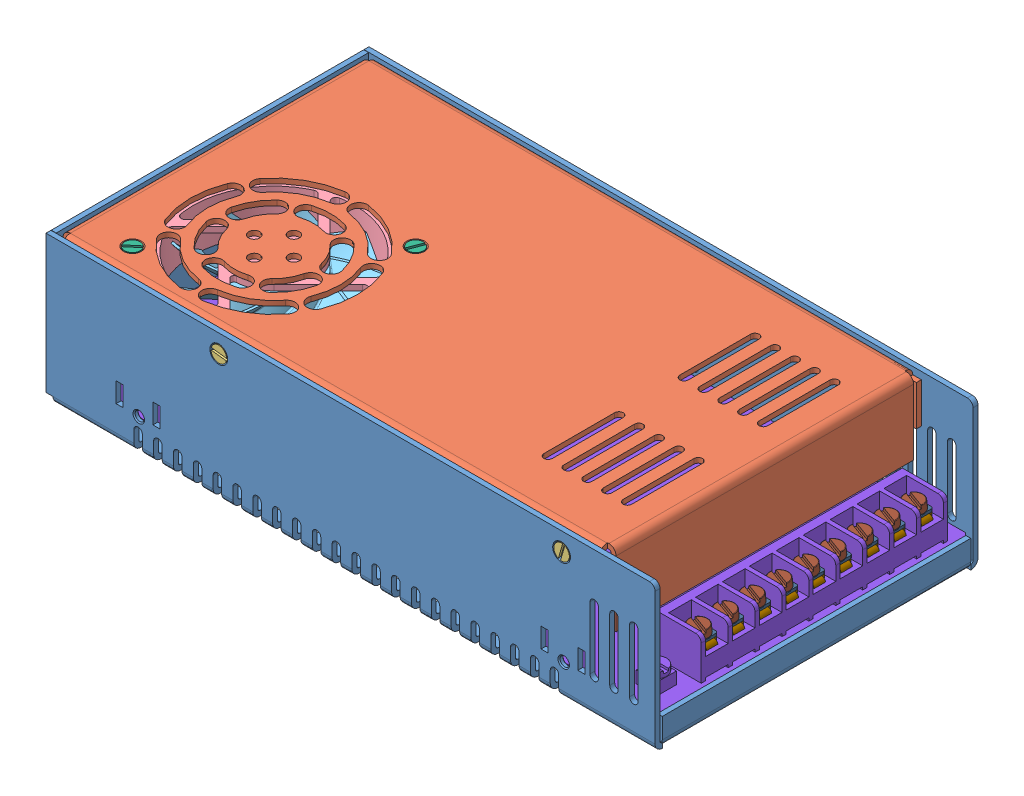
SolidWorks assembly PSU, configuration Default. Lengths in mm.
Overall size (215 51.25 117.38).
46 component instances, 12 part files, 0 mates.
Components (placement in the parent):
- SWP (Basis)-1: SWP (Basis) [Default] at (0 1.75 57) x (1 0 0) z (0 1 0) size (215 114 51.25)
- SWP (Deksel)-1: SWP (Deksel) [Default] at (-18.25 51.25 57) x (1 0 0) z (0 1 0) size (195 110.5 25.75)
- Slotted Countersunk Flat Head Screw_DIN_ISO 2009 - M3 x 5 --- 5N-1: Slotted Countersunk Flat Head Screw_DIN_ISO 2009 - M3 x 5 --- 5N [Default] at (-154 44.75 114) x (0 0 -1) z (-0.992092 0.125515 0) size (5 5.5 5.44)
- Slotted Countersunk Flat Head Screw_DIN_ISO 2009 - M3 x 5 --- 5N-2: Slotted Countersunk Flat Head Screw_DIN_ISO 2009 - M3 x 5 --- 5N [Default] at (-33 44.75 114) x (0 0 -1) z (0.278156 0.960536 0) size (5 5.5 5.44)
- Slotted Countersunk Flat Head Screw_DIN_ISO 2009 - M3 x 5 --- 5N-3: Slotted Countersunk Flat Head Screw_DIN_ISO 2009 - M3 x 5 --- 5N [Default] at (-154 44.75 0) x (0 0 1) z (0 1 0) size (5 5.5 5.44)
- Slotted Countersunk Flat Head Screw_DIN_ISO 2009 - M3 x 5 --- 5N-4: Slotted Countersunk Flat Head Screw_DIN_ISO 2009 - M3 x 5 --- 5N [Default] at (-33 44.75 0) x (0 0 1) z (-0.877705 -0.479201 0) size (5 5.5 5.44)
- Slotted Countersunk Flat Head Screw_DIN_ISO 2009 - M3 x 5 --- 5N-5: Slotted Countersunk Flat Head Screw_DIN_ISO 2009 - M3 x 5 --- 5N [Default] at (-215 44.75 102) x (1 0 0) z (0 0.869235 -0.494399) size (5 5.5 5.44)
- Slotted Countersunk Flat Head Screw_DIN_ISO 2009 - M3 x 5 --- 5N-6: Slotted Countersunk Flat Head Screw_DIN_ISO 2009 - M3 x 5 --- 5N [Default] at (-215 44.75 12) x (1 0 0) z (0 0.76206 0.647506) size (5 5.5 5.44)
- Body 60mm fan-1: Body 60mm fan [Default] at (-170.75 34.3 77.75) x (1 0 0) z (0 1 0) size (59.5 59.5 15.2)
- Propellor 60mm fan-1: Propellor 60mm fan [Default] at (-170.75 44.3 77.75) x (0.544808 0 -0.838561) z (0 1 0) size (57.61 57.23 10.49)
- Slotted Countersunk Flat Head Screw_DIN_ISO 2009 - M3 x 20 --- 20N-1: Slotted Countersunk Flat Head Screw_DIN_ISO 2009 - M3 x 20 --- 20N [Default] at (-145.75 51.25 52.75) x (0 -1 0) z (0.364765 0 -0.9311) size (20 5.5 5.44)
- Slotted Countersunk Flat Head Screw_DIN_ISO 2009 - M3 x 20 --- 20N-2: Slotted Countersunk Flat Head Screw_DIN_ISO 2009 - M3 x 20 --- 20N [Default] at (-195.75 51.25 102.75) x (0 -1 0) z (0.762204 0 -0.647337) size (20 5.5 5.44)
- SWP (M3 moer)-1: SWP (M3 moer) [Default] at (-205 0 104.5) x (1 0 0) z (0 1 0) size (8.08 7 3.75)
- SWP (M3 moer)-2: SWP (M3 moer) [Default] at (-205 0 9.5) x (1 0 0) z (0 1 0) size (8.08 7 3.75)
- SWP (M3 moer)-3: SWP (M3 moer) [Default] at (-117.5 0 50.05) x (1 0 0) z (0 1 0) size (8.08 7 3.75)
- SWP (M3 moer)-4: SWP (M3 moer) [Default] at (-27.5 0 104.5) x (1 0 0) z (0 1 0) size (8.08 7 3.75)
- SWP (M3 moer)-5: SWP (M3 moer) [Default] at (-27.5 0 9.5) x (1 0 0) z (0 1 0) size (8.08 7 3.75)
- SWP (PCB)-1: SWP (PCB) [Default] at (-1.75 9.75 57) x (1 0 0) z (0 1 0) size (211.5 110.5 15.9)
- SWP (Montage draad)_1-1: SWP (Montage draad)_1 [Default] at (-9.8 18.4 88.95) x (0 0 1) z (0 1 0) size (7 9.9 4.25)
- SWP (Montage draad 2)_1-1: SWP (Montage draad 2)_1 [Default] at (-9.8 18.4 88.95) x (1 0 0) z (0 1 0) size (7 7 1)
- Slotted Cheese Head Screw_DIN_ISO 1207 - M4 x 5 --- 5N-1: Slotted Cheese Head Screw_DIN_ISO 1207 - M4 x 5 --- 5N [Default] at (-9.8 22 88.95) x (0 -1 0) z (0.939291 0 0.343123) size (7.61 7 7)
- SWP (Montage draad)_1-2: SWP (Montage draad)_1 [Default] at (-9.8 18.4 79.45) x (0 0 1) z (0 1 0) size (7 9.9 4.25)
- SWP (Montage draad)_1-3: SWP (Montage draad)_1 [Default] at (-9.8 18.4 69.95) x (0 0 1) z (0 1 0) size (7 9.9 4.25)
- SWP (Montage draad)_1-4: SWP (Montage draad)_1 [Default] at (-9.8 18.4 60.45) x (0 0 1) z (0 1 0) size (7 9.9 4.25)
- SWP (Montage draad)_1-5: SWP (Montage draad)_1 [Default] at (-9.8 18.4 50.95) x (0 0 1) z (0 1 0) size (7 9.9 4.25)
- SWP (Montage draad)_1-6: SWP (Montage draad)_1 [Default] at (-9.8 18.4 41.45) x (0 0 1) z (0 1 0) size (7 9.9 4.25)
- SWP (Montage draad)_1-7: SWP (Montage draad)_1 [Default] at (-9.8 18.4 31.95) x (0 0 1) z (0 1 0) size (7 9.9 4.25)
- SWP (Montage draad)_1-8: SWP (Montage draad)_1 [Default] at (-9.8 18.4 22.45) x (0 0 1) z (0 1 0) size (7 9.9 4.25)
- SWP (Montage draad)_1-9: SWP (Montage draad)_1 [Default] at (-9.8 18.4 12.95) x (0 0 1) z (0 1 0) size (7 9.9 4.25)
- SWP (Montage draad 2)_1-2: SWP (Montage draad 2)_1 [Default] at (-9.8 18.4 79.45) x (1 0 0) z (0 1 0) size (7 7 1)
- SWP (Montage draad 2)_1-3: SWP (Montage draad 2)_1 [Default] at (-9.8 18.4 69.95) x (1 0 0) z (0 1 0) size (7 7 1)
- SWP (Montage draad 2)_1-4: SWP (Montage draad 2)_1 [Default] at (-9.8 18.4 60.45) x (1 0 0) z (0 1 0) size (7 7 1)
- SWP (Montage draad 2)_1-5: SWP (Montage draad 2)_1 [Default] at (-9.8 18.4 50.95) x (1 0 0) z (0 1 0) size (7 7 1)
- SWP (Montage draad 2)_1-6: SWP (Montage draad 2)_1 [Default] at (-9.8 18.4 41.45) x (1 0 0) z (0 1 0) size (7 7 1)
- SWP (Montage draad 2)_1-7: SWP (Montage draad 2)_1 [Default] at (-9.8 18.4 31.95) x (1 0 0) z (0 1 0) size (7 7 1)
- SWP (Montage draad 2)_1-8: SWP (Montage draad 2)_1 [Default] at (-9.8 18.4 22.45) x (1 0 0) z (0 1 0) size (7 7 1)
- SWP (Montage draad 2)_1-9: SWP (Montage draad 2)_1 [Default] at (-9.8 18.4 12.95) x (1 0 0) z (0 1 0) size (7 7 1)
- Slotted Cheese Head Screw_DIN_ISO 1207 - M4 x 5 --- 5N-2: Slotted Cheese Head Screw_DIN_ISO 1207 - M4 x 5 --- 5N [Default] at (-9.8 22 79.45) x (0 -1 0) z (0.939291 0 0.343123) size (7.61 7 7)
- Slotted Cheese Head Screw_DIN_ISO 1207 - M4 x 5 --- 5N-3: Slotted Cheese Head Screw_DIN_ISO 1207 - M4 x 5 --- 5N [Default] at (-9.8 22 69.95) x (0 -1 0) z (0.939291 0 0.343123) size (7.61 7 7)
- Slotted Cheese Head Screw_DIN_ISO 1207 - M4 x 5 --- 5N-4: Slotted Cheese Head Screw_DIN_ISO 1207 - M4 x 5 --- 5N [Default] at (-9.8 22 60.45) x (0 -1 0) z (0.939291 0 0.343123) size (7.61 7 7)
- Slotted Cheese Head Screw_DIN_ISO 1207 - M4 x 5 --- 5N-5: Slotted Cheese Head Screw_DIN_ISO 1207 - M4 x 5 --- 5N [Default] at (-9.8 22 50.95) x (0 -1 0) z (0.939291 0 0.343123) size (7.61 7 7)
- Slotted Cheese Head Screw_DIN_ISO 1207 - M4 x 5 --- 5N-6: Slotted Cheese Head Screw_DIN_ISO 1207 - M4 x 5 --- 5N [Default] at (-9.8 22 41.45) x (0 -1 0) z (0.939291 0 0.343123) size (7.61 7 7)
- Slotted Cheese Head Screw_DIN_ISO 1207 - M4 x 5 --- 5N-7: Slotted Cheese Head Screw_DIN_ISO 1207 - M4 x 5 --- 5N [Default] at (-9.8 22 31.95) x (0 -1 0) z (0.939291 0 0.343123) size (7.61 7 7)
- Slotted Cheese Head Screw_DIN_ISO 1207 - M4 x 5 --- 5N-8: Slotted Cheese Head Screw_DIN_ISO 1207 - M4 x 5 --- 5N [Default] at (-9.8 22 22.45) x (0 -1 0) z (0.939291 0 0.343123) size (7.61 7 7)
- Slotted Cheese Head Screw_DIN_ISO 1207 - M4 x 5 --- 5N-9: Slotted Cheese Head Screw_DIN_ISO 1207 - M4 x 5 --- 5N [Default] at (-9.8 22 12.95) x (0 -1 0) z (0.939291 0 0.343123) size (7.61 7 7)
- SWP (switch)-1: SWP (switch) [Default] at (-128.5 14.3 0) x (-1 0 0) z (0 0 -1) size (19 12.1 6)
